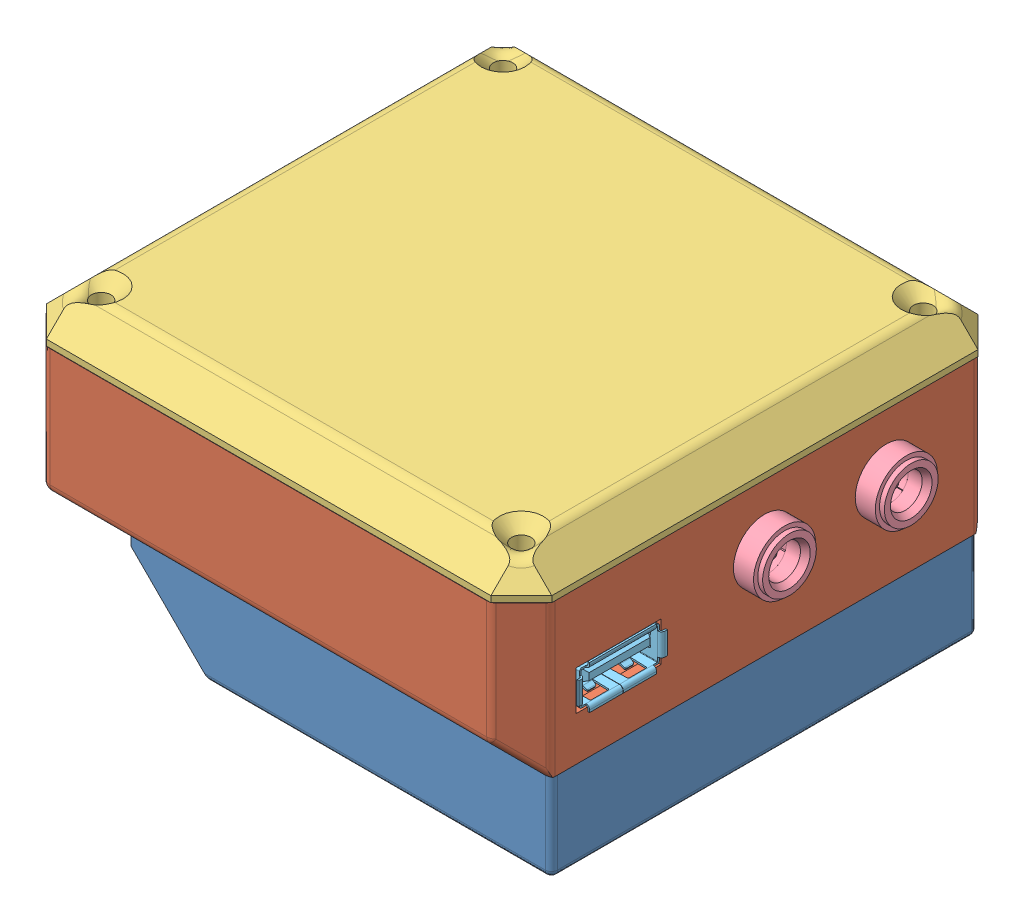
SolidWorks assembly Assem2, configuration Default. Lengths in mm.
Overall size (87.1 45.5 80.06).
6 component instances, 5 part files, 11 mates.
Components (placement in the parent):
- base batterie-1: base batterie [Default] at (52.1673 39.5969 62.4303) size (78.59 14.5 70)
- box-1: box [Default] at (32.8159 54.0969 62.4303) x (0 0 1) z (-1 0 0) size (80 25 83)
- cover-1: cover [Default] at (32.8159 79.0969 62.3702) x (0 0 1) z (0 1 0) size (80 83 14.8)
- DC Jack Panel Mount Base-1: DC Jack Panel Mount Base [Default] at (77.6159 69.0969 42.4303) x (0 0.938567 0.345096) z (1 0 0) size (10.2 10.2 17.63)
- DC Jack Panel Mount Base-2: DC Jack Panel Mount Base [Default] at (77.6159 69.0969 62.4303) x (0 0 1) z (1 0 0) size (10.2 10.2 17.63)
- USB Connector Type A female-1: USB Connector Type A female [Default] at (74.3159 65.6327 86.2505) x (0 0 -1) z (1 0 0) size (15.82 11.39 14.17)
Mates (geometry in assembly coordinates):
- Coincident5: coincident anti-aligned: plane of base batterie-1 through (-3.6841 54.0969 62.4303) normal (0 1 0); plane of box-1 through (32.8159 54.0969 62.4303) normal (0 -1 0)
- Concentric1: concentric anti-aligned: circle of base batterie-1; circle of box-1
- Concentric2: concentric anti-aligned: circle of base batterie-1; circle of box-1
- Concentric3: concentric aligned: circle of box-1; circle of cover-1
- Concentric4: concentric aligned: circle of box-1; circle of cover-1
- Coincident6: coincident anti-aligned: plane of box-1 through (32.8159 79.0969 62.4303) normal (0 1 0); plane of cover-1 through (32.8159 79.0969 62.3702) normal (0 -1 0)
- Concentric5: concentric anti-aligned: circle of box-1; circle of DC Jack Panel Mount Base-2
- Coincident11: coincident anti-aligned: plane of box-1 through (74.3159 79.0969 22.4303) normal (1 0 0); plane of DC Jack Panel Mount Base-2 through (74.3159 69.0969 67.5303) normal (-1 0 0)
- Concentric6: concentric anti-aligned: circle of box-1; circle of DC Jack Panel Mount Base-1
- Coincident12: coincident anti-aligned: plane of box-1 through (74.3159 79.0969 22.4303) normal (1 0 0); plane of DC Jack Panel Mount Base-1 through (74.3159 73.8836 44.1903) normal (-1 0 0)
- Coincident13: coincident aligned: plane of box-1 through (74.3159 79.0969 22.4303) normal (1 0 0); plane of USB Connector Type A female-1 through (74.3159 65.6327 86.2505) normal (1 0 0)
